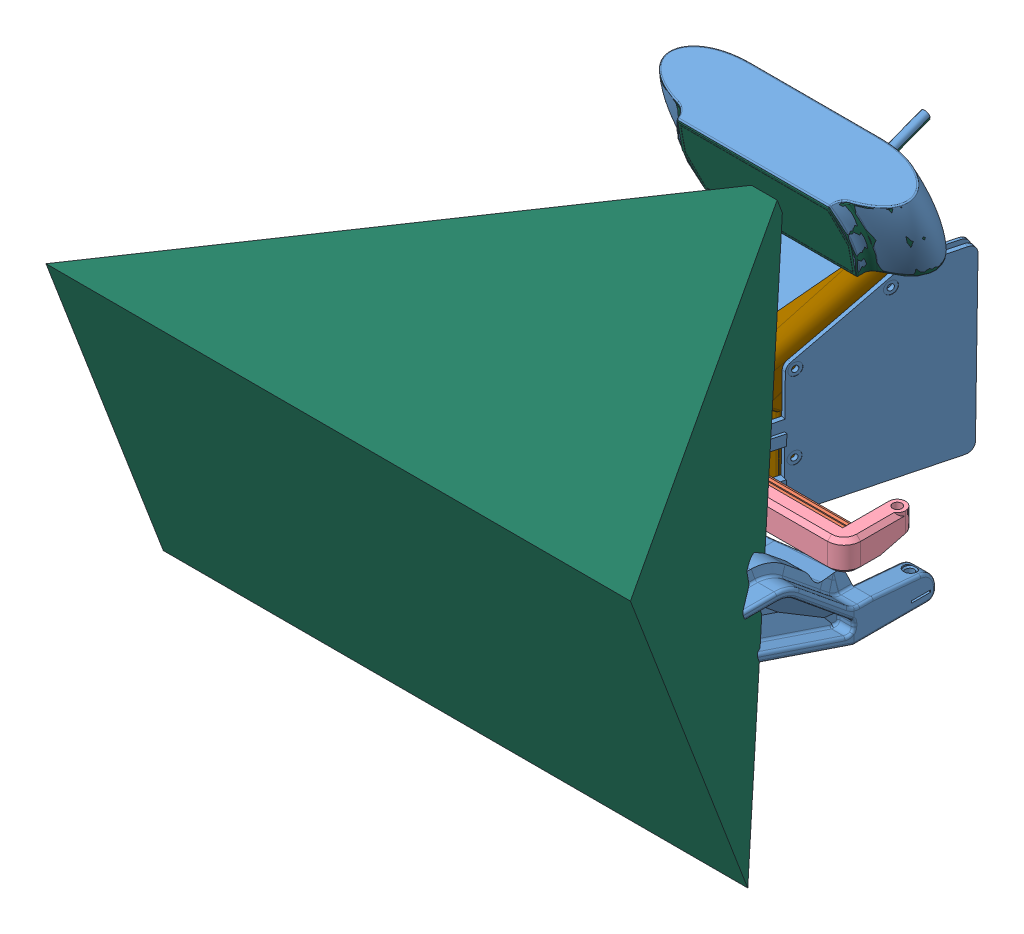
SolidWorks assembly Gripper_Assy, configuration Default. Lengths in mm.
Overall size (155.61 270.24 560.65).
29 component instances, 18 part files, 63 mates.
Components (placement in the parent):
- Gripper_Master-1: Gripper_Master [Default] at origin size (155.61 270.24 560.55)
- MGN7_Rail-1: MGN7_Rail [80mm] at (78.25 9 479.159) x (0 1 0) z (-1 0 0) size (7 4.8 80)
- MGN7_Rail-2: MGN7_Rail [80mm] at (21.75 -9 479.159) x (0 1 0) z (-1 0 0) size (7 4.8 80)
- MGN7C_Carriage-1: MGN7C_Carriage [Default] at (0 9 476.709) x (0 -1 0) z (1 0 0) size (17 6.5 23.48)
- MGN7C_Carriage-2: MGN7C_Carriage [Default] at (0 -9 476.709) x (0 -1 0) z (1 0 0) size (17 6.5 23.48)
- Gripper_Jaw-1: Gripper_Jaw [Default] at (56.5 0 0.1) size (95.56 32.39 102.84)
- Gripper_Jaw-2: Gripper_Jaw [Default] at (-56.5 0 0.1) x (-1 0 0) z (0 0 1) size (95.56 32.39 102.84)
- XL-430-1: XL-430 [Default] at (0 0 436.709) x (-1 0 0) z (0 0 1) size (28.5 46.5 34)
- 430_Horn-1: 430_Horn [Default] at (0 0 436.959) x (-0.999988 0.004902 0) z (0 0 1) size (20.5 20.5 4.15)
- Gripper_Carriage_Mount-1: Gripper_Carriage_Mount [Default] at origin size (34.5 55.1 3.18)
- Gripper_Drive_Pulley-1: Gripper_Drive_Pulley [Default] x (-0.978523 0.206138 0) z (0 0 1) size (27 27 12.75)
- Gripper_Structure-1: Gripper_Structure [Default] at origin size (59.82 80.07 58.27)
- CF_Spring_Idler-1: CF_Spring_Idler [Default] at (-19.402 17.1492 0) x (0.122802 -0.992431 0) z (0 0 1) size (9.1 9.1 8.94)
- CF_Spring_Idler-2: CF_Spring_Idler [Default] at (-7.4466 -37.6262 0) x (0.924615 -0.380902 0) z (0 0 1) size (9.1 9.1 8.94)
- 91292A831_18-8 Stainless Steel Socket Head Screw-1: 91292A831_18-8 Stainless Steel Socket Head Screw [91292A831] at (1.75 -9 485.059) x (-0.599094 -0.800678 0) z (0 0 1) size (3.8 3.8 8.1)
- 92125A051_18-8 Stainless Steel Hex Drive Flat Head Screw-1: 92125A051_18-8 Stainless Steel Hex Drive Flat Head Screw [92125A051] at (-4 15 472.924) x (-1 0 0) z (0 0 -1) size (4 4 5.21)
- 92125A059_18-8 Stainless Steel Hex Drive Flat Head Screw-1: 92125A059_18-8 Stainless Steel Hex Drive Flat Head Screw [92125A059] at (0 19.55 465.319) size (4 4 16.28)
- 92010A775_Passivated 18-8 Stainless Steel Phillips Flat Head Screw-1: 92010A775_Passivated 18-8 Stainless Steel Phillips Flat Head Screw [92010A775] at (-11 8 455.309) size (4.7 4.7 6.14)
- 92010A775_Passivated 18-8 Stainless Steel Phillips Flat Head Screw-2: 92010A775_Passivated 18-8 Stainless Steel Phillips Flat Head Screw [92010A775] at (11 8 455.309) x (-0.583056 -0.812432 0) z (0 0 1) size (4.7 4.7 6.14)
- 92125A059_18-8 Stainless Steel Hex Drive Flat Head Screw-2: 92125A059_18-8 Stainless Steel Hex Drive Flat Head Screw [92125A059] at (0 -19.55 465.319) x (0.987351 0.158553 0) z (0 0 1) size (4 4 16.28)
- C922X_Pro-1: C922X_Pro [Tilted Down] at (-0.0197 67.771 437.1221) x (1 0 0) z (0 0.123477 0.992347) size (211.74 160.55 195.68)
- 92000A108_Passivated 18-8 Stainless Steel Pan Head Phillips Screws-1: 92000A108_Passivated 18-8 Stainless Steel Pan Head Phillips Screws [92000A108] at (-11 32 449.159) x (0.327132 -0.944979 0) z (0 0 1) size (5 5 16.27)
- 92000A108_Passivated 18-8 Stainless Steel Pan Head Phillips Screws-2: 92000A108_Passivated 18-8 Stainless Steel Pan Head Phillips Screws [92000A108] at (11 32 449.159) x (-0.176447 -0.98431 0) z (0 0 1) size (5 5 16.27)
- 92000A108_Passivated 18-8 Stainless Steel Pan Head Phillips Screws-4: 92000A108_Passivated 18-8 Stainless Steel Pan Head Phillips Screws [92000A108] at (-11 -8 449.159) x (-0.17128 0.985222 0) z (0 0 1) size (5 5 16.27)
- 92000A108_Passivated 18-8 Stainless Steel Pan Head Phillips Screws-6: 92000A108_Passivated 18-8 Stainless Steel Pan Head Phillips Screws [92000A108] at (11.0621 -7.7578 449.159) x (-0.164848 -0.986319 0) z (0 0 1) size (5 5 16.27)
- CF_Spring_Idler_Cap-1: CF_Spring_Idler_Cap [Default] at origin size (9.1 9.1 1)
- CF_Spring_Idler_Cap-2: CF_Spring_Idler_Cap [Default] at (0 -39.1 0) size (9.1 9.1 1)
- 0.1x8x110_CF-2: 0.1x8x110_CF [9293K111] at (0 -19.55 465.1902) x (0 0 1) z (0 1 0) size (8.01 10.11 7.57)
- 0.1x8x110_CF-1: 0.1x8x110_CF [9293K111] at (0 19.55 465.1902) x (0 0 1) z (0 -1 0) size (8.01 10.11 7.57)
Mates (geometry in assembly coordinates):
- Width1: width anti-aligned: plane of MGN7C_Carriage-1 through (6.75 12.5 476.709) normal (0 -1 0); plane of MGN7_Rail-1 through (6.75 5.5 476.709) normal (0 1 0); plane of MGN7C_Carriage-1 through (-21.75 12.5 477.4652) normal (0 1 0); plane of MGN7_Rail-1 through (-21.75 5.5 477.4652) normal (0 -1 0)
- Coincident7: coincident anti-aligned: plane of MGN7_Rail-1 through (-21.75 5.7 476.759) normal (0 0 -1); plane of MGN7C_Carriage-1 through (6.75 9 476.759) normal (0 0 1)
- Coincident8: coincident: line of Gripper_Master-1 through (-11.25 17.5 473.459) axis (0 -1 0); plane of MGN7C_Carriage-1 through (-11.25 9 476.709) normal (-1 0 0)
- Coincident9: coincident anti-aligned: plane of Gripper_Master-1 through (0 0 473.459) normal (0 0 1); plane of MGN7C_Carriage-1 through (6.75 9 473.459) normal (0 0 -1)
- Coincident11: coincident: line of Gripper_Master-1 through (11.25 17.5 473.459) axis (-1 0 0); plane of MGN7C_Carriage-1 through (6.75 17.5 476.709) normal (0 1 0)
- Coincident12: coincident: line of Gripper_Master-1 through (-11.25 -17.5 473.459) axis (1 0 0); plane of MGN7C_Carriage-2 through (6.75 -17.5 476.709) normal (0 -1 0)
- Coincident13: coincident: line of Gripper_Master-1 through (11.25 -0.5 473.459) axis (0 -1 0); plane of MGN7C_Carriage-2 through (11.25 -9 476.709) normal (1 0 0)
- Coincident14: coincident anti-aligned: plane of Gripper_Master-1 through (0 0 473.459) normal (0 0 1); plane of MGN7C_Carriage-2 through (6.75 -9 473.459) normal (0 0 -1)
- Coincident15: coincident anti-aligned: plane of MGN7_Rail-2 through (-78.25 -12.3 476.759) normal (0 0 -1); plane of MGN7C_Carriage-2 through (6.75 -9 476.759) normal (0 0 1)
- Width2: width anti-aligned: plane of MGN7_Rail-2 through (-78.25 -12.5 477.4652) normal (0 -1 0); plane of MGN7C_Carriage-2 through (-78.25 -5.5 477.4652) normal (0 1 0); plane of MGN7_Rail-2 through (6.75 -12.5 476.709) normal (0 1 0); plane of MGN7C_Carriage-2 through (6.75 -5.5 476.709) normal (0 -1 0)
- Linear/Linear Coupler1: linear coupler = 0.001 : 0.001 mm: plane of MGN7_Rail-1 through (-11.75 5.5 481.559) normal (-1 0 0); plane of MGN7_Rail-2 through (11.75 -12.5 481.559) normal (1 0 0)
- Coincident35: coincident anti-aligned: plane of MGN7_Rail-1 through (68.25 5.5 481.559) normal (1 0 0); plane of Gripper_Jaw-1 through (68.25 0 468.029) normal (-1 0 0)
- Coincident36: coincident anti-aligned: plane of MGN7_Rail-1 through (-21.75 5.7 481.559) normal (0 0 1); plane of Gripper_Jaw-1 through (-12.5 0 481.559) normal (0 0 -1)
- Coincident37: coincident anti-aligned: plane of MGN7_Rail-2 through (-68.25 -12.5 481.559) normal (-1 0 0); plane of Gripper_Jaw-2 through (-68.25 0 468.029) normal (1 0 0)
- Coincident38: coincident anti-aligned: plane of MGN7_Rail-2 through (-78.25 -12.3 481.559) normal (0 0 1); plane of Gripper_Jaw-2 through (12.5 0 481.559) normal (0 0 -1)
- Concentric3: concentric anti-aligned: line of XL-430-1 through (0 0 455.5591) axis (0 0 -1); cylinder of 430_Horn-1 through (0 0 452.459) axis (0 0 1) radius 10.25
- Coincident39: coincident anti-aligned: plane of XL-430-1 through (0 0 453.709) normal (0 0 1); plane of 430_Horn-1 through (10.9766 -4.8039 453.709) normal (0 0 -1)
- Coincident40: coincident anti-aligned: line of Gripper_Master-1 through (0 0 353.5534) axis (0 0 1); line of XL-430-1 through (0 0 455.5591) axis (0 0 -1)
- Concentric4: concentric aligned: cylinder of CF_Spring_Idler-1 through (0 19.55 470.159) axis (0 0 1) radius 2.8; circle of 0.1x8x110_CF-1
- Width5: width aligned: plane of 0.1x8x110_CF-1 through (0.514 16.635 469.1902) normal (0 0 1); plane of CF_Spring_Idler-1 through (0.514 16.635 461.1902) normal (0 0 -1); plane of 0.1x8x110_CF-1 through (-19.402 17.1492 470.159) normal (0 0 1); plane of CF_Spring_Idler_Cap-1 through (0 0 460.2215) normal (0 0 -1)
- Concentric7: concentric aligned: cylinder of MGN7_Rail-1 through (-1.75 9 481.56) axis (0 0 -1) radius 1.2; cylinder of Gripper_Jaw-1 through (-1.75 9 492.2259) axis (0 0 -1) radius 1.65
- Coincident42: coincident anti-aligned: plane of MGN7C_Carriage-1 through (6.75 9 473.459) normal (0 0 -1); plane of Gripper_Carriage_Mount-1 through (0 0 473.459) normal (0 0 1)
- Concentric8: concentric aligned: cylinder of MGN7C_Carriage-1 through (4 15 473.459) axis (0 0 -1) radius 0.8; cylinder of Gripper_Carriage_Mount-1 through (4 15 470.284) axis (0 0 -1) radius 1.1
- Concentric9: concentric aligned: cylinder of MGN7C_Carriage-1 through (-4 15 473.459) axis (0 0 -1) radius 0.8; cylinder of Gripper_Carriage_Mount-1 through (-4 15 470.284) axis (0 0 -1) radius 1.1
- Concentric11: concentric aligned: cylinder of Gripper_Carriage_Mount-1 through (0 19.55 473.459) axis (0 0 1) radius 1.1; cylinder of Gripper_Structure-1 through (0 19.55 456.0965) axis (0 0 1) radius 1.65
- Concentric12: concentric aligned: cylinder of Gripper_Carriage_Mount-1 through (0 -19.55 473.459) axis (0 0 1) radius 1.1; cylinder of Gripper_Structure-1 through (0 -19.55 456.0965) axis (0 0 1) radius 1.65
- Concentric13: concentric aligned: cylinder of Gripper_Carriage_Mount-1 through (0 19.55 473.459) axis (0 0 1) radius 1.1; cylinder of CF_Spring_Idler-1 through (0 19.55 470.159) axis (0 0 1) radius 1.1
- Concentric14: concentric aligned: cylinder of Gripper_Carriage_Mount-1 through (0 -19.55 473.459) axis (0 0 1) radius 1.1; cylinder of CF_Spring_Idler-2 through (0 -19.55 470.159) axis (0 0 1) radius 1.1
- Concentric15: concentric aligned: cylinder of MGN7_Rail-2 through (1.75 -9 481.56) axis (0 0 -1) radius 1.2; cylinder of Gripper_Jaw-2 through (1.75 -9 492.2259) axis (0 0 -1) radius 1.65
- LimitDistance2: limit distance = 0.5 mm aligned: plane of MGN7_Rail-2 through (11.75 -12.5 481.559) normal (1 0 0); plane of MGN7C_Carriage-2 through (11.25 -9 476.709) normal (1 0 0)
- Coincident47: coincident aligned: cone of Gripper_Structure-1 through (-11 8 457.209) axis (0 0 -1); cone of 92010A775_Passivated 18-8 Stainless Steel Phillips Flat Head Screw-1 through (-11 8 455.759) axis (0 0 -1)
- Coincident48: coincident aligned: cone of Gripper_Carriage_Mount-1 through (-4 15 470.284) axis (0 0 1); cone of 92125A051_18-8 Stainless Steel Hex Drive Flat Head Screw-1 through (-4 15 470.484) axis (0 0 1)
- Concentric17: concentric aligned: circle of MGN7_Rail-2; circle of 91292A831_18-8 Stainless Steel Socket Head Screw-1
- Coincident49: coincident anti-aligned: plane of MGN7_Rail-2 through (1.75 -9 479.059) normal (0 0 -1); plane of 91292A831_18-8 Stainless Steel Socket Head Screw-1 through (1.75 -9 479.059) normal (0 0 1)
- Coincident50: coincident aligned: cone of Gripper_Carriage_Mount-1 through (0 19.55 473.459) axis (0 0 -1); cone of 92125A059_18-8 Stainless Steel Hex Drive Flat Head Screw-1 through (0 19.55 473.259) axis (0 0 -1)
- Coincident55: coincident aligned: cone of Gripper_Structure-1 through (11 8 457.209) axis (0 0 -1); cone of 92010A775_Passivated 18-8 Stainless Steel Phillips Flat Head Screw-2 through (11 8 455.759) axis (0 0 -1)
- Coincident56: coincident aligned: cone of Gripper_Carriage_Mount-1 through (0 -19.55 473.459) axis (0 0 -1); cone of 92125A059_18-8 Stainless Steel Hex Drive Flat Head Screw-2 through (0 -19.55 473.259) axis (0 0 -1)
- Concentric22: concentric anti-aligned: cylinder of 430_Horn-1 through (0 0 455.959) axis (0 0 1) radius 4; cylinder of Gripper_Drive_Pulley-1 through (0 0 353.5534) axis (0 0 -1) radius 10
- Coincident61: coincident anti-aligned: plane of 430_Horn-1 through (0 0 455.959) normal (0 0 1); plane of Gripper_Drive_Pulley-1 through (0 0 455.959) normal (0 0 -1)
- Concentric23: concentric aligned: cylinder of XL-430-1 through (-11 32 449.089) axis (0 0 1) radius 1.3; cylinder of Gripper_Structure-1 through (-11 32 457.209) axis (0 0 1) radius 2.75
- Concentric24: concentric aligned: circle of Gripper_Structure-1; circle of 92000A108_Passivated 18-8 Stainless Steel Pan Head Phillips Screws-1
- Coincident63: coincident anti-aligned: plane of Gripper_Structure-1 through (-9.65 32 455.109) normal (0 0 1); plane of 92000A108_Passivated 18-8 Stainless Steel Pan Head Phillips Screws-1 through (-12.7968 31.378 455.109) normal (0 0 -1)
- Concentric25: concentric aligned: circle of 92000A108_Passivated 18-8 Stainless Steel Pan Head Phillips Screws-2; cylinder of Gripper_Structure-1 through (11 32 457.209) axis (0 0 1) radius 1.35
- Coincident64: coincident anti-aligned: plane of Gripper_Structure-1 through (9.65 32 455.109) normal (0 0 1); plane of 92000A108_Passivated 18-8 Stainless Steel Pan Head Phillips Screws-2 through (9.1284 32.3355 455.109) normal (0 0 -1)
- Concentric26: concentric aligned: circle of Gripper_Structure-1; circle of 92000A108_Passivated 18-8 Stainless Steel Pan Head Phillips Screws-4
- Coincident65: coincident anti-aligned: plane of Gripper_Structure-1 through (-9.65 -8 455.109) normal (0 0 1); plane of 92000A108_Passivated 18-8 Stainless Steel Pan Head Phillips Screws-4 through (-9.1266 -7.6743 455.109) normal (0 0 -1)
- Concentric28: concentric aligned: cylinder of Gripper_Structure-1 through (-25.869 104.6369 411.3326) axis (0 -0.992347 0.123477) radius 1.1; cylinder of C922X_Pro-1 through (-25.869 56.366 417.3389) axis (0 -0.992347 0.123477) radius 1.65
- Parallel3: parallel aligned: plane of C922X_Pro-1 through (-0.0197 67.771 437.1221) normal (1 0 0)
- Coincident68: coincident anti-aligned: plane of XL-430-1 through (0 0 453.709) normal (0 0 1); plane of Gripper_Structure-1 through (0 0 453.709) normal (0 0 -1)
- Coincident69: coincident anti-aligned: plane of Gripper_Structure-1 through (-52.8473 51.9944 430.7975) normal (0 0.992347 -0.123477); plane of C922X_Pro-1 through (29.48 49.6711 412.1257) normal (0 -0.992347 0.123477)
- Tangent1: tangent aligned: cylinder of Gripper_Structure-1 through (11 -8 457.209) axis (0 0 1) radius 2.75; torus of 92000A108_Passivated 18-8 Stainless Steel Pan Head Phillips Screws-6
- Coincident70: coincident anti-aligned: plane of Gripper_Structure-1 through (9.65 -8 455.109) normal (0 0 1); plane of 92000A108_Passivated 18-8 Stainless Steel Pan Head Phillips Screws-6 through (9.1867 -7.4444 455.109) normal (0 0 -1)
- Coincident74: coincident anti-aligned: plane of Gripper_Carriage_Mount-1 through (0 0 470.284) normal (0 0 -1); plane of Gripper_Structure-1 through (0 0 470.284) normal (0 0 1)
- Parallel5: parallel: line of 0.1x8x110_CF-1 through (2 15.6473 465.1902) axis (1 0 0)
- Concentric29: concentric aligned: cylinder of CF_Spring_Idler-2 through (0 -19.55 470.159) axis (0 0 1) radius 2.8; circle of 0.1x8x110_CF-2
- Width6: width aligned: plane of 0.1x8x110_CF-2 through (-0.514 -16.635 461.1902) normal (0 0 -1); plane of 0.1x8x110_CF-2 through (-0.514 -16.635 469.1902) normal (0 0 1); plane of CF_Spring_Idler_Cap-2 through (0 -39.1 460.2215) normal (0 0 -1); plane of CF_Spring_Idler-2 through (-7.4466 -37.6262 470.159) normal (0 0 1)
- Parallel6: parallel: line of 0.1x8x110_CF-2 through (-2 -15.6473 465.1902) axis (-1 0 0)
- Coincident75: coincident anti-aligned: plane of CF_Spring_Idler-2 through (-7.4466 -37.6262 461.2215) normal (0 0 -1); plane of CF_Spring_Idler_Cap-2 through (0 -39.1 461.2215) normal (0 0 1)
- Width7: width anti-aligned: plane of CF_Spring_Idler-2 through (-7.4466 -37.6262 470.159) normal (0 0 1); plane of CF_Spring_Idler_Cap-2 through (0 -39.1 460.2215) normal (0 0 -1); plane of Gripper_Carriage_Mount-1 through (0 0 470.284) normal (0 0 -1); plane of Gripper_Structure-1 through (0 -19.55 460.0965) normal (0 0 1)
- Coincident76: coincident anti-aligned: plane of CF_Spring_Idler-1 through (-19.402 17.1492 461.2215) normal (0 0 -1); plane of CF_Spring_Idler_Cap-1 through (0 0 461.2215) normal (0 0 1)
- Width8: width anti-aligned: plane of CF_Spring_Idler-1 through (-19.402 17.1492 470.159) normal (0 0 1); plane of CF_Spring_Idler_Cap-1 through (0 0 460.2215) normal (0 0 -1); plane of Gripper_Carriage_Mount-1 through (0 0 470.284) normal (0 0 -1); plane of Gripper_Structure-1 through (0 19.55 460.0965) normal (0 0 1)
- Concentric30: concentric aligned: cylinder of Gripper_Structure-1 through (0 19.55 456.0965) axis (0 0 1) radius 1.65; cylinder of CF_Spring_Idler_Cap-1 through (0 19.55 470.159) axis (0 0 1) radius 1.1
- Concentric31: concentric aligned: cylinder of Gripper_Structure-1 through (0 -19.55 456.0965) axis (0 0 1) radius 1.65; cylinder of CF_Spring_Idler_Cap-2 through (0 -19.55 470.159) axis (0 0 1) radius 1.1
